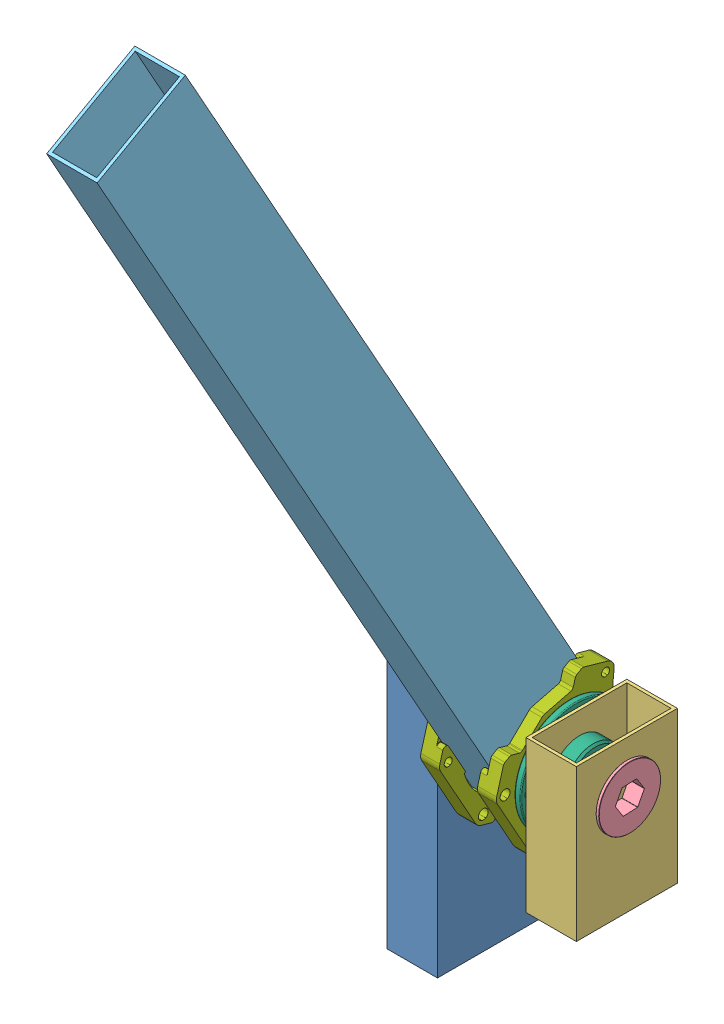
SolidWorks assembly Climber vsomething, configuration Default. Lengths in mm.
Overall size (101.11 491.65 276.9).
10 component instances, 7 part files, 24 mates.
Components (placement in the parent):
- Climb Mount large-1: Climb Mount large [Default] at (52.6266 16.6141 118.8348) x (0 0 1) z (0 1 0) size (50.8 25.4 127)
- Climb axle-1: Climb axle [Default] at (124.4915 118.2141 118.8348) x (0 0.886216 -0.463271) z (-1 0 0) size (14.66 12.7 88.9)
- Climb Mount small-1: Climb Mount small [Default] at (122.4766 67.4141 118.8348) x (0 0 -1) z (0 1 0) size (50.8 25.4 76.2)
- am-2986 FR8ZZ Hex Bearing.step-1: am-2986 FR8ZZ Hex Bearing.step [Default] at (128.7732 118.2141 118.8348) x (0 0.886216 -0.463271) z (1 0 0) size (31.12 31.12 7.93)
- am-2986 FR8ZZ Hex Bearing.step-3: am-2986 FR8ZZ Hex Bearing.step [Default] at (46.3299 118.2141 118.8348) x (0 0 1) z (-1 0 0) size (31.12 31.12 7.93)
- Lower climb arm-1: Lower climb arm [Default] at (87.5516 96.7864 105.1112) x (0 -0.487925 0.872885) z (-1 0 0) size (50.8 457.2 25.4)
- 1_2” Hex Bore Aluminum VersaHub (217-2592).step-1: 1_2” Hex Bore Aluminum VersaHub (217-2592).step [Default] at (55.8016 118.2141 118.8348) x (1 0 0) z (0 -0.487925 0.872885) size (12.7 55.88 55.88)
- 1_2” Hex Bore Aluminum VersaHub (217-2592).step-2: 1_2” Hex Bore Aluminum VersaHub (217-2592).step [Default] at (119.3016 118.2141 118.8348) x (-1 0 0) z (0 -0.511978 -0.858998) size (12.7 55.88 55.88)
- VersaBlock V2 (217-6111).step-1: VersaBlock V2 (217-6111).step [Default] at (71.6766 118.2141 118.8348) x (0 0.872885 0.487925) z (-1 0 0) size (61.04 66.67 9.53)
- VersaBlock V2 (217-6111).step-2: VersaBlock V2 (217-6111).step [Default] at (103.4266 118.2141 118.8348) x (0 -0.872885 -0.487925) z (1 0 0) size (61.04 66.67 9.53)
Mates (geometry in assembly coordinates):
- Concentric1: concentric anti-aligned: cylinder of Climb Mount large-1 through (65.3266 118.2141 118.8348) axis (-1 0 0) radius 14.2875; cylinder of Climb Mount small-1 through (109.7766 118.2141 118.8348) axis (1 0 0) radius 14.2875
- Coincident1: coincident aligned: plane of Climb Mount large-1 through (52.6266 143.6141 118.8348) normal (0 1 0); plane of Climb Mount small-1 through (122.4766 143.6141 118.8348) normal (0 1 0)
- Coincident4: coincident anti-aligned: plane of Climb Mount small-1 through (135.1766 143.6141 93.4348) normal (1 0 0); plane of am-2986 FR8ZZ Hex Bearing.step-1 through (135.1766 130.5945 112.3629) normal (-1 0 0)
- Concentric3: concentric anti-aligned: cylinder of Climb Mount small-1 through (109.7766 118.2141 118.8348) axis (1 0 0) radius 14.2875; cylinder of am-2986 FR8ZZ Hex Bearing.step-1 through (136.7006 118.2141 118.8348) axis (-1 0 0) radius 14.2875
- Coincident6: coincident anti-aligned: plane of Climb Mount large-1 through (39.9266 143.6141 144.2348) normal (-1 0 0); plane of am-2986 FR8ZZ Hex Bearing.step-3 through (39.9266 118.2141 132.8048) normal (1 0 0)
- Concentric5: concentric anti-aligned: line of Climb Mount large-1 through (65.3266 118.2141 118.8348) axis (-1 0 0); axis of am-2986 FR8ZZ Hex Bearing.step-3 through (40.4346 118.2141 118.8348) axis (1 0 0)
- Coincident7: coincident anti-aligned: plane of Climb axle-1 through (35.5915 117.9068 126.1607) normal (0 0.463271 0.886216); plane of am-2986 FR8ZZ Hex Bearing.step-1 through (136.7006 117.9068 126.1607) normal (0 -0.463271 -0.886216)
- Coincident8: coincident anti-aligned: plane of Climb axle-1 through (35.5915 124.7121 115.4379) normal (0 0.53585 -0.844313); plane of am-2986 FR8ZZ Hex Bearing.step-1 through (136.7006 124.7121 115.4379) normal (0 -0.53585 0.844313)
- Coincident10: coincident anti-aligned: plane of Lower climb arm-1 through (74.8516 483.4763 350.362) normal (-1 0 0); plane of VersaBlock V2 (217-6111).step-1 through (74.8516 118.2141 118.8348) normal (1 0 0)
- Coincident11: coincident anti-aligned: plane of Lower climb arm-1 through (74.8516 483.4763 350.362) normal (0 -0.487925 0.872885); plane of VersaBlock V2 (217-6111).step-1 through (-4.6404 133.2032 154.5663) normal (0 0.487925 -0.872885)
- Coincident12: coincident anti-aligned: plane of Lower climb arm-1 through (74.8516 483.4763 350.362) normal (0 -0.487925 0.872885); plane of VersaBlock V2 (217-6111).step-2 through (179.7436 79.9256 124.7852) normal (0 0.487925 -0.872885)
- Coincident13: coincident anti-aligned: plane of Lower climb arm-1 through (100.2516 483.4763 350.362) normal (1 0 0); plane of VersaBlock V2 (217-6111).step-2 through (100.2516 118.2141 118.8348) normal (-1 0 0)
- Parallel1: parallel anti-aligned: plane of Climb Mount small-1 through (109.7766 143.6141 93.4348) normal (-1 0 0); plane of Lower climb arm-1 through (100.2516 483.4763 350.362) normal (1 0 0)
- Concentric6: concentric anti-aligned: cylinder of Lower climb arm-1 through (-356.9484 118.2141 118.8348) axis (1 0 0) radius 12.7; cylinder of VersaBlock V2 (217-6111).step-1 through (113.7106 118.2141 118.8348) axis (-1 0 0) radius 14.2748
- Concentric7: concentric aligned: cylinder of Lower climb arm-1 through (-356.9484 118.2141 118.8348) axis (1 0 0) radius 12.7; cylinder of VersaBlock V2 (217-6111).step-2 through (61.3926 118.2141 118.8348) axis (1 0 0) radius 14.2748
- Coincident16: coincident anti-aligned: plane of 1_2” Hex Bore Aluminum VersaHub (217-2592).step-2 through (106.6016 145.3127 102.6835) normal (-1 0 0); plane of VersaBlock V2 (217-6111).step-2 through (106.6016 118.5448 142.645) normal (1 0 0)
- Concentric8: concentric anti-aligned: cylinder of 1_2” Hex Bore Aluminum VersaHub (217-2592).step-2 through (192.3949 97.4285 107.2161) axis (-1 0 0) radius 2.15; cylinder of VersaBlock V2 (217-6111).step-2 through (106.6016 97.4285 107.2161) axis (1 0 0) radius 2.4892
- Concentric9: concentric anti-aligned: cylinder of 1_2” Hex Bore Aluminum VersaHub (217-2592).step-2 through (192.3949 97.7592 131.0263) axis (-1 0 0) radius 2.15; cylinder of VersaBlock V2 (217-6111).step-2 through (106.6016 97.7592 131.0263) axis (1 0 0) radius 1.7272
- Coincident17: coincident anti-aligned: plane of 1_2” Hex Bore Aluminum VersaHub (217-2592).step-1 through (68.5016 145.7508 134.2273) normal (1 0 0); plane of VersaBlock V2 (217-6111).step-1 through (68.5016 97.7592 131.0263) normal (-1 0 0)
- Concentric10: concentric anti-aligned: cylinder of 1_2” Hex Bore Aluminum VersaHub (217-2592).step-1 through (-17.2918 97.4285 107.2161) axis (1 0 0) radius 2.15; cylinder of VersaBlock V2 (217-6111).step-1 through (68.5016 97.4285 107.2161) axis (-1 0 0) radius 2.4892
- Concentric11: concentric anti-aligned: cylinder of 1_2” Hex Bore Aluminum VersaHub (217-2592).step-1 through (-17.2918 97.7592 131.0263) axis (1 0 0) radius 2.15; cylinder of VersaBlock V2 (217-6111).step-1 through (68.5016 97.7592 131.0263) axis (-1 0 0) radius 1.7272
- Concentric12: concentric anti-aligned: cylinder of Climb Mount small-1 through (109.7766 118.2141 118.8348) axis (1 0 0) radius 14.2875; cylinder of 1_2” Hex Bore Aluminum VersaHub (217-2592).step-2 through (106.6016 118.2141 118.8348) axis (-1 0 0) radius 14.2949
- Coincident18: coincident anti-aligned: plane of Climb Mount small-1 through (109.7766 143.6141 93.4348) normal (-1 0 0); plane of 1_2” Hex Bore Aluminum VersaHub (217-2592).step-2 through (109.7766 130.4934 111.5161) normal (1 0 0)
- Coincident20: coincident anti-aligned: plane of Climb Mount large-1 through (65.3266 143.6141 144.2348) normal (1 0 0); plane of 1_2” Hex Bore Aluminum VersaHub (217-2592).step-1 through (65.3266 130.6919 125.8096) normal (-1 0 0)
